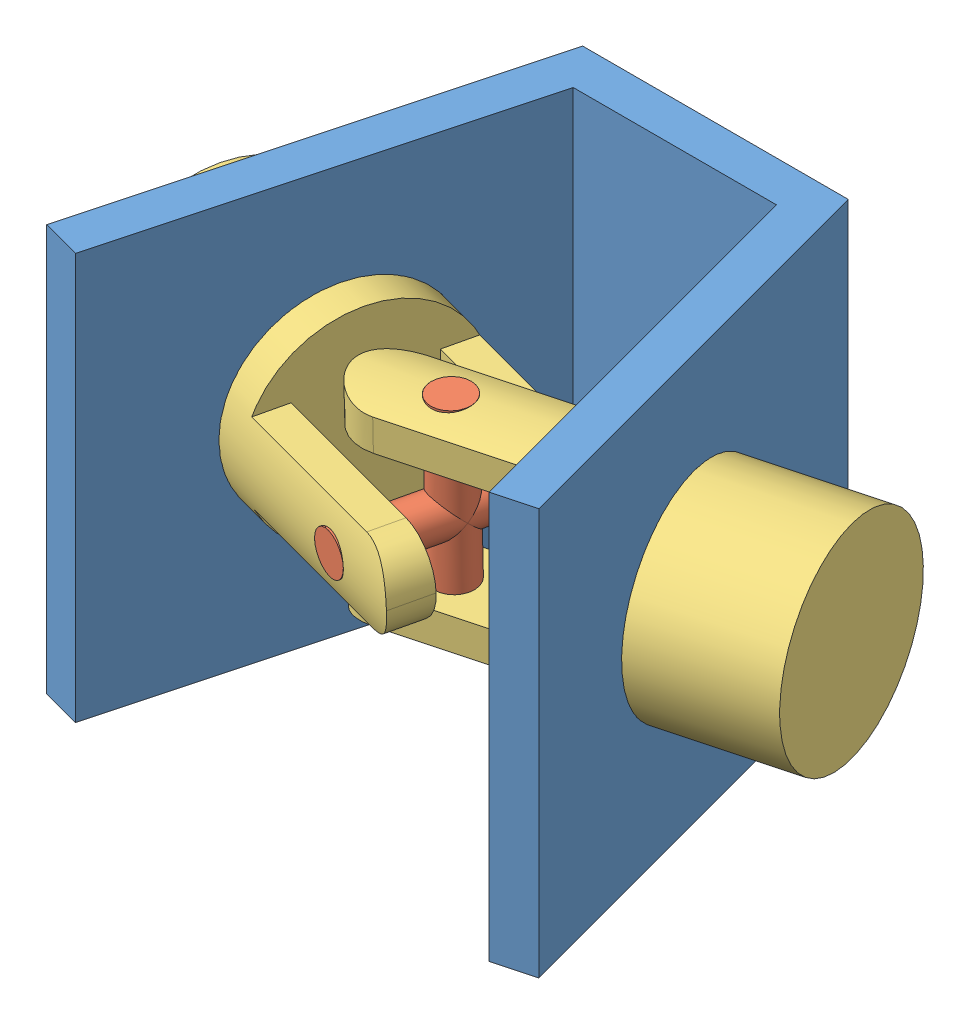
SolidWorks assembly Kardan, configuration Standard. Lengths in mm.
Overall size (33.57 20 21.32).
4 component instances, 3 part files, 9 mates.
Components (placement in the parent):
- Kardan-Block-1: Kardan-Block [Standard] at origin size (24.22 20 21.32)
- Kardan-1-1: Kardan-1 [Standard] at (0 0 10.8981) x (0.008399 0.999473 0.031346) z (-0.965917 0.016219 -0.258344) size (10 10 2)
- Kardan-2-1: Kardan-2 [Standard] at (-5.7956 0 9.3452) x (0.965926 0 0.258819) z (-0.007275 0.999605 0.02715) size (20 10 10)
- Kardan-2-2: Kardan-2 [Standard] at (5.7956 0 9.3452) x (-0.965926 0 0.258819) z (-0.258683 0.032452 -0.965417) size (20 10 10)
Mates (geometry in assembly coordinates):
- Konzentrisch1: concentric anti-aligned: cylinder of Kardan-1-1 through (1.2936 0.1405 6.0704) axis (-0.258717 -0.028108 0.965544) radius 1; cylinder of Kardan-2-1 through (-1.2936 -0.1405 15.7258) axis (0.258717 0.028108 -0.965544) radius 1
- Konzentrisch2: concentric anti-aligned: cylinder of Kardan-1-1 through (0.042 4.9974 11.0548) axis (-0.008399 -0.999473 -0.031346) radius 1; cylinder of Kardan-2-2 through (-0.042 -4.9974 10.7414) axis (0.008399 0.999473 0.031346) radius 1
- Deckungsgleich1: coincident aligned: plane of Kardan-Block-1 through (0 0 0) normal (1 0 0); plane of assembly through (0 0 0) normal (1 0 0)
- Deckungsgleich2: coincident aligned: plane of Kardan-Block-1 through (0 0 0) normal (0 1 0); plane of assembly through (0 0 0) normal (0 1 0)
- Deckungsgleich3: coincident aligned: plane of Kardan-Block-1 through (0 0 0) normal (0 0 1); plane of assembly through (0 0 0) normal (0 0 1)
- Konzentrisch3: concentric aligned: cylinder of Kardan-Block-1 through (13.4034 0 14.4895) axis (-0.965926 0 -0.258819) radius 5; cylinder of Kardan-2-1 through (3.8637 0 11.9334) axis (-0.965926 0 -0.258819) radius 5
- Konzentrisch4: concentric aligned: cylinder of Kardan-Block-1 through (-13.4034 0 14.4895) axis (0.965926 0 -0.258819) radius 5; cylinder of Kardan-2-2 through (-3.8637 0 11.9334) axis (0.965926 0 -0.258819) radius 5
- Deckungsgleich4: coincident: point of Kardan-1-1; line of Kardan-2-1 through (3.8637 0 11.9334) axis (-0.965926 0 -0.258819)
- Deckungsgleich6: coincident: point of Kardan-1-1; line of Kardan-2-2 through (-3.8637 0 11.9334) axis (0.965926 0 -0.258819)
